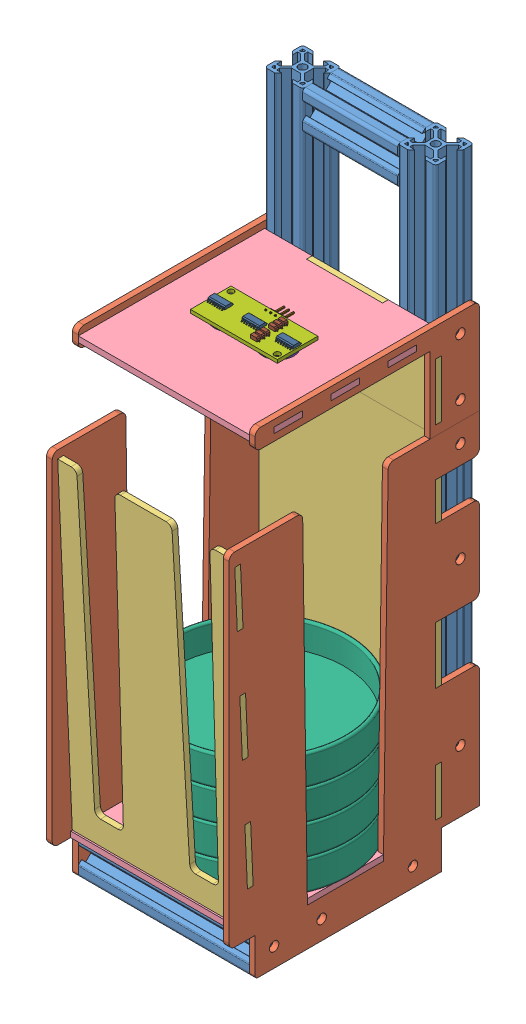
SolidWorks assembly Stack, configuration PetriDish93. Lengths in mm.
Overall size (132.29 320 136.14).
32 component instances, 11 part files, 52 mates.
Components (placement in the parent):
- V-Slot 20mm x 20mm x 1000mm-1: V-Slot 20mm x 20mm x 1000mm [300] at (-474.1607 34.7961 856.1691) x (1 0 0) z (0 -1 0) size (20 20 300)
- V-Slot 20mm x 20mm x 1000mm-2: V-Slot 20mm x 20mm x 1000mm [300] at (-404.1607 34.7961 856.1691) x (1 0 0) z (0 -1 0) size (20 20 300)
- V-Slot 20mm x 20mm x 1000mm-3: V-Slot 20mm x 20mm x 1000mm [50] at (-414.1607 44.7961 856.1691) x (0 0 -1) z (1 0 0) size (20 20 50)
- V-Slot 20mm x 20mm x 1000mm-4: V-Slot 20mm x 20mm x 1000mm [50] at (-414.1607 324.7961 856.1691) x (0 0 -1) z (1 0 0) size (20 20 50)
- Sides-1: Sides [Default] at (-487.1607 14.7961 866.1691) size (3 250 131.69)
- FrontBack-1: FrontBack [Default] at (-484.1607 38.948 964.3536) x (1 0 0) z (0 -0.044401 0.999014) size (96 173 3)
- FrontBack-2: FrontBack [Back] at (-484.1607 14.7961 866.1691) size (96 246.5 3)
- Sides-3: Sides [Default] at (-394.1607 14.7961 866.1691) size (3 250 131.69)
- Top-1: Top [Default] at (-484.1607 258.2961 964.1691) size (96 3 98)
- V-Slot 20mm x 20mm x 1000mm-5: V-Slot 20mm x 20mm x 1000mm [75] at (-404.1607 24.7961 944.1691) size (20 20 75)
- V-Slot 20mm x 20mm x 1000mm-6: V-Slot 20mm x 20mm x 1000mm [75] at (-474.1607 24.7961 944.1691) size (20 20 75)
- Top-2: Top [Bottom] at (-484.1607 34.7961 964.1691) size (96 3 102)
- V-Slot 20mm x 20mm x 1000mm-7: V-Slot 20mm x 20mm x 1000mm [90] at (-484.1607 24.7961 954.1691) x (0 0 1) z (-1 0 0) size (20 20 90)
- ElectronicsPlatform-1: ElectronicsPlatform [Default] at (-407.7607 26.4568 869.1691) x (1 0 0) z (0 0 -1) size (63 4 81.5)
- GlassDish-1: GlassDish [94_16] at (-436.9246 85.7961 916.1691) x (0.940581 0 0.339568) z (-0.339568 0 0.940581) size (94 16 94)
- GlassDish-2: GlassDish [94_16] at (-436.9246 37.7961 916.1691) x (-0.604504 0 0.796602) z (-0.796602 0 -0.604504) size (94 16 94)
- GlassDish-3: GlassDish [94_16] at (-436.9246 69.7961 916.1691) x (0.07957 0 -0.996829) z (0.996829 0 0.07957) size (94 16 94)
- GlassDish-4: GlassDish [94_16] at (-436.9246 53.7961 916.1691) x (0.773515 0 -0.633778) z (0.633778 0 0.773515) size (94 16 94)
- Parallax Ping Sensor-1: Parallax Ping Sensor [Default] at (-439.1607 266.0461 916.6691) x (0 0 -1) z (0 -1 0) size (29.3 45.7 15.59)
  - Parallax Ping PCB-1: Parallax Ping PCB [Default] at origin size (21.3 45.7 1.75)
  - Parallax Ping Transducer-1: Parallax Ping Transducer [Default] at (0 -12.69 13.25) x (1 0 0) z (0 -1 0) size (16.3 12 16.3)
  - Parallax Ping Transducer-2: Parallax Ping Transducer [Default] at (0 12.69 13.25) x (1 0 0) z (0 -1 0) size (16.3 12 16.3)
  - 3 Pin Header 90 Degree-1: 3 Pin Header 90 Degree [Default] at (11.4 0 3.25) x (0 0 1) z (0 -1 0) size (5.5 10.32 8)
  - 14 Pin SMT-1: 14 Pin SMT [Default] at (0 -17.87 -0.85) x (1 0 0) z (0 1 0) size (6 1.6 8.8)
  - 14 Pin SMT-2: 14 Pin SMT [Default] at (0 0.04 -0.85) x (1 0 0) z (0 1 0) size (6 1.6 8.8)
  - 14 Pin SMT-3: 14 Pin SMT [Default] at (0 17.95 -0.85) x (1 0 0) z (0 1 0) size (6 1.6 8.8)
  - Cap1 SMT-1: Cap1 SMT [Default] at (-2.155 7.9 -0.9689) x (0 1 0) z (-1 0 0) size (4.5 1.84 1.75)
  - Cap1 SMT-2: Cap1 SMT [Default] at (7.235 7.9 -0.9689) x (0 1 0) z (-1 0 0) size (4.5 1.84 1.75)
  - Cap1 SMT-3: Cap1 SMT [Default] at (-7.235 7.9 -0.9689) x (0 1 0) z (-1 0 0) size (4.5 1.84 1.75)
  - Cap1 SMT-4: Cap1 SMT [Default] at (4.695 7.9 -0.9689) x (0 1 0) z (-1 0 0) size (4.5 1.84 1.75)
  - Cap1 SMT-5: Cap1 SMT [Default] at (2.155 7.9 -0.9689) x (0 1 0) z (-1 0 0) size (4.5 1.84 1.75)
  - Cap1 SMT-6: Cap1 SMT [Default] at (-4.695 7.9 -0.9689) x (0 1 0) z (-1 0 0) size (4.5 1.84 1.75)
Mates (geometry in assembly coordinates):
- Tangent12: tangent: plane of GlassDish-3 through (-436.9246 69.7961 916.1691) normal (0 -1 0); torus of GlassDish-4
- Tangent14: tangent: plane of GlassDish-1 through (-436.9246 85.7961 916.1691) normal (0 -1 0); torus of GlassDish-3
- Concentric4: concentric aligned: circle of GlassDish-2; circle of GlassDish-4
- Concentric5: concentric aligned: circle of GlassDish-2; circle of GlassDish-3
- Concentric6: concentric aligned: circle of GlassDish-2; circle of GlassDish-1
- Coincident99: coincident aligned: plane of V-Slot 20mm x 20mm x 1000mm-2 through (-399.2535 334.7961 846.1691) normal (0 0 -1); plane of V-Slot 20mm x 20mm x 1000mm-3 through (-464.1607 49.7033 846.1691) normal (0 0 -1)
- Coincident100: coincident aligned: plane of V-Slot 20mm x 20mm x 1000mm-2 through (-413.3707 34.7961 851.2619) normal (0 -1 0); plane of V-Slot 20mm x 20mm x 1000mm-3 through (-464.1607 34.7961 851.2619) normal (0 -1 0)
- Coincident101: coincident anti-aligned: plane of V-Slot 20mm x 20mm x 1000mm-2 through (-414.1607 334.7961 851.2619) normal (-1 0 0); plane of V-Slot 20mm x 20mm x 1000mm-3 through (-414.1607 39.8889 865.3791) normal (1 0 0)
- Coincident102: coincident aligned: plane of V-Slot 20mm x 20mm x 1000mm-1 through (-483.3707 34.7961 851.2619) normal (0 -1 0); plane of V-Slot 20mm x 20mm x 1000mm-3 through (-464.1607 34.7961 861.0763) normal (0 -1 0)
- Coincident103: coincident anti-aligned: plane of V-Slot 20mm x 20mm x 1000mm-1 through (-464.1607 334.7961 851.2619) normal (1 0 0); plane of V-Slot 20mm x 20mm x 1000mm-3 through (-464.1607 39.8889 865.3791) normal (-1 0 0)
- Coincident104: coincident aligned: plane of V-Slot 20mm x 20mm x 1000mm-1 through (-469.2535 334.7961 846.1691) normal (0 0 -1); plane of V-Slot 20mm x 20mm x 1000mm-3 through (-464.1607 39.8889 846.1691) normal (0 0 -1)
- Coincident105: coincident anti-aligned: plane of V-Slot 20mm x 20mm x 1000mm-3 through (-464.1607 49.7033 866.1691) normal (0 0 1); plane of FrontBack-2 through (-484.1607 14.7961 866.1691) normal (0 0 -1)
- Coincident110: coincident anti-aligned: plane of V-Slot 20mm x 20mm x 1000mm-6 through (-479.0679 34.7961 869.1691) normal (0 1 0); plane of Top-2 through (-484.1607 34.7961 964.1691) normal (0 -1 0)
- Coincident111: coincident anti-aligned: plane of V-Slot 20mm x 20mm x 1000mm-5 through (-409.0679 34.7961 869.1691) normal (0 1 0); plane of Top-2 through (-484.1607 34.7961 964.1691) normal (0 -1 0)
- Coincident112: coincident anti-aligned: plane of FrontBack-2 through (-484.1607 14.7961 869.1691) normal (0 0 1); plane of V-Slot 20mm x 20mm x 1000mm-5 through (-413.3707 19.8889 869.1691) normal (0 0 -1)
- Coincident113: coincident anti-aligned: plane of FrontBack-2 through (-484.1607 14.7961 869.1691) normal (0 0 1); plane of V-Slot 20mm x 20mm x 1000mm-6 through (-483.3707 19.8889 869.1691) normal (0 0 -1)
- Distance5: distance = 20 mm aligned: plane of V-Slot 20mm x 20mm x 1000mm-3 through (-464.1607 34.7961 861.0763) normal (0 -1 0); plane of FrontBack-2 through (-484.1607 14.7961 869.1691) normal (0 -1 0)
- Coincident116: coincident anti-aligned: plane of Sides-1 through (-484.1607 14.7961 866.1691) normal (1 0 0); plane of V-Slot 20mm x 20mm x 1000mm-6 through (-484.1607 29.7033 869.1691) normal (-1 0 0)
- Coincident117: coincident aligned: plane of Sides-1 through (-484.1607 14.7961 866.1691) normal (0 -1 0); plane of FrontBack-2 through (-484.1607 14.7961 869.1691) normal (0 -1 0)
- Coincident119: coincident anti-aligned: plane of Sides-1 through (-484.1607 14.7961 866.1691) normal (1 0 0); plane of Top-2 through (-484.1607 37.7961 964.1691) normal (-1 0 0)
- Concentric7: concentric anti-aligned: cylinder of V-Slot 20mm x 20mm x 1000mm-7 through (-394.1607 24.7961 954.1691) axis (-1 0 0) radius 2.1; cylinder of Sides-1 through (-488.1607 24.7961 954.1691) axis (1 0 0) radius 2.5
- Coincident121: coincident anti-aligned: plane of Sides-1 through (-484.1607 14.7961 866.1691) normal (1 0 0); plane of V-Slot 20mm x 20mm x 1000mm-7 through (-484.1607 19.8889 944.9591) normal (-1 0 0)
- Coincident125: coincident anti-aligned: plane of Top-2 through (-484.1607 34.7961 964.1691) normal (0 -1 0); plane of V-Slot 20mm x 20mm x 1000mm-7 through (-394.1607 34.7961 949.2619) normal (0 1 0)
- Coincident127: coincident anti-aligned: plane of Sides-1 through (-484.1607 14.7961 866.1691) normal (1 0 0); plane of Top-1 through (-484.1607 261.2961 964.1691) normal (-1 0 0)
- Coincident129: coincident aligned: plane of FrontBack-2 through (-484.1607 14.7961 869.1691) normal (0 -1 0); plane of Sides-3 through (-391.1607 14.7961 866.1691) normal (0 -1 0)
- Coincident131: coincident anti-aligned: plane of Sides-3 through (-394.1607 14.7961 866.1691) normal (-1 0 0); plane of Top-2 through (-394.1607 37.7961 964.1691) normal (1 0 0)
- Coincident135: coincident aligned: plane of V-Slot 20mm x 20mm x 1000mm-1 through (-483.3707 334.7961 851.2619) normal (0 1 0); plane of V-Slot 20mm x 20mm x 1000mm-4 through (-464.1607 334.7961 861.0763) normal (0 1 0)
- Coincident136: coincident anti-aligned: plane of V-Slot 20mm x 20mm x 1000mm-1 through (-464.1607 334.7961 851.2619) normal (1 0 0); plane of V-Slot 20mm x 20mm x 1000mm-4 through (-464.1607 319.8889 865.3791) normal (-1 0 0)
- Coincident137: coincident aligned: plane of V-Slot 20mm x 20mm x 1000mm-1 through (-469.2535 334.7961 846.1691) normal (0 0 -1); plane of V-Slot 20mm x 20mm x 1000mm-4 through (-464.1607 329.7033 846.1691) normal (0 0 -1)
- Tangent15: tangent anti-aligned: plane of FrontBack-2 through (-484.1607 14.7961 869.1691) normal (0 0 1); cylinder of GlassDish-2 through (-436.9246 53.7961 916.1691) axis (0 -1 0) radius 47
- Coincident138: coincident anti-aligned: plane of Top-2 through (-484.1607 37.7961 964.1691) normal (0 1 0); plane of GlassDish-2 through (-436.9246 37.7961 916.1691) normal (0 -1 0)
- Coincident140: coincident: line of Top-2 through (-394.1607 34.7961 896.6691) axis (0 1 0); cylinder of GlassDish-2 through (-436.9246 53.7961 916.1691) axis (0 -1 0) radius 47
- Parallel8: parallel aligned: plane of Top-2 through (-484.1607 34.7961 964.1691) normal (0 -1 0); plane of ElectronicsPlatform-1 through (-407.7607 22.4568 869.1691) normal (0 -1 0)
- Parallel9: parallel aligned: plane of ElectronicsPlatform-1 through (-470.7607 22.4568 950.6691) normal (0 0 1); plane of Top-2 through (-484.1607 34.7961 968.1691) normal (0 0 1)
- Coincident143: coincident anti-aligned: plane of FrontBack-2 through (-484.1607 14.7961 869.1691) normal (0 0 1); plane of ElectronicsPlatform-1 through (-470.7607 22.4568 869.1691) normal (0 0 -1)
- Coincident144: coincident anti-aligned: plane of V-Slot 20mm x 20mm x 1000mm-6 through (-470.7607 22.4568 869.1691) normal (1 0 0); plane of ElectronicsPlatform-1 through (-470.7607 22.4568 950.6691) normal (-1 0 0)
- Coincident145: coincident anti-aligned: plane of Sides-1 through (-487.1607 10.4886 963.0888) normal (0 -0.044401 0.999014); plane of FrontBack-1 through (-484.1607 38.948 964.3536) normal (0 0.044401 -0.999014)
- Coincident147: coincident anti-aligned: plane of Sides-1 through (-487.1607 14.7961 879.1691) normal (0 0 1); plane of Top-1 through (-487.1607 258.2961 879.1691) normal (0 0 -1)
- Coincident148: coincident anti-aligned: plane of Sides-1 through (-484.1607 14.7961 866.1691) normal (1 0 0); plane of FrontBack-1 through (-484.1607 38.8148 967.3507) normal (-1 0 0)
- Coincident149: coincident anti-aligned: plane of Sides-1 through (-487.1607 62.2368 868.2776) normal (0 0.999014 0.044401); plane of FrontBack-1 through (-484.1607 57.7961 968.1943) normal (0 -0.999014 -0.044401)
- Coincident150: coincident anti-aligned: plane of Sides-3 through (-394.1607 14.7961 866.1691) normal (-1 0 0); plane of V-Slot 20mm x 20mm x 1000mm-5 through (-394.1607 19.8889 869.1691) normal (1 0 0)
- Coincident152: coincident: line of V-Slot 20mm x 20mm x 1000mm-6 through (-470.7607 22.4568 869.1691) axis (0 0 1); plane of ElectronicsPlatform-1 through (-407.7607 22.4568 869.1691) normal (0 -1 0)
- Coincident153: coincident anti-aligned: plane of FrontBack-2 through (-484.1607 14.7961 869.1691) normal (0 0 1); plane of Top-2 through (-484.1607 37.7961 869.1691) normal (0 0 -1)
- Tangent17: tangent: torus of GlassDish-2; plane of GlassDish-4 through (-436.9246 53.7961 916.1691) normal (0 -1 0)
- Coincident154: coincident anti-aligned: plane of V-Slot 20mm x 20mm x 1000mm-1 through (-484.1607 334.7961 861.0763) normal (-1 0 0); plane of Sides-1 through (-484.1607 14.7961 866.1691) normal (1 0 0)
- Coincident155: coincident anti-aligned: plane of FrontBack-2 through (-484.1607 14.7961 869.1691) normal (0 0 1); plane of Sides-3 through (-391.1607 129.7961 869.1691) normal (0 0 -1)
- Concentric8: concentric anti-aligned: cylinder of Sides-3 through (-395.1607 24.7961 954.1691) axis (1 0 0) radius 2.5; cylinder of V-Slot 20mm x 20mm x 1000mm-7 through (-394.1607 24.7961 954.1691) axis (-1 0 0) radius 2.1
- Coincident157: coincident anti-aligned: plane of FrontBack-2 through (-394.1607 14.7961 869.1691) normal (1 0 0); plane of Sides-3 through (-394.1607 14.7961 866.1691) normal (-1 0 0)
- Coincident158: coincident anti-aligned: plane of Sides-1 through (-487.1607 261.2961 866.1691) normal (0 -1 0); plane of Top-1 through (-484.1607 261.2961 964.1691) normal (0 1 0)
- Concentric9: concentric anti-aligned: cylinder of Top-1 through (-451.8507 258.296 916.6691) axis (0 1 0) radius 8.15; cylinder of Parallax Ping Sensor-1/Parallax Ping Transducer-1 through (-451.8507 252.7961 916.6691) axis (0 -1 0) radius 8.15
- Concentric10: concentric anti-aligned: cylinder of Top-1 through (-426.4707 258.296 916.6691) axis (0 1 0) radius 8.15; cylinder of Parallax Ping Sensor-1/Parallax Ping Transducer-2 through (-426.4707 252.7961 916.6691) axis (0 -1 0) radius 8.15
- Coincident159: coincident anti-aligned: plane of Top-1 through (-484.1607 261.2961 964.1691) normal (0 1 0); plane of Parallax Ping Sensor-1/3 Pin Header 90 Degree-1 through (-443.1607 261.2961 906.5191) normal (0 -1 0)
